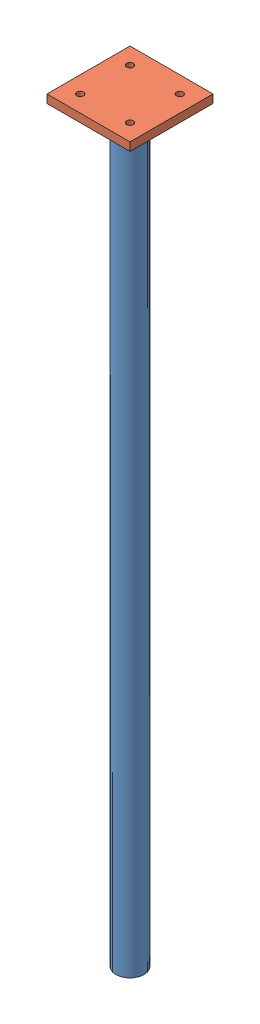
SolidWorks assembly НожкаУГ, configuration По умолчанию. Lengths in mm.
Overall size (100 910 100).
2 component instances, 2 part files, 3 mates.
Components (placement in the parent):
- Ножка-1: Ножка [По умолчанию] at origin size (34 900 34)
- ПланкаУГл-1: ПланкаУГл [По умолчанию] at (0 910 0) x (0 0 -1) z (-1 0 0) size (100 10 100)
Mates (geometry in assembly coordinates):
- Совпадение10: coincident anti-aligned: plane of Ножка-1 through (0 900 0) normal (0 1 0); plane of ПланкаУГл-1 through (0 900 0) normal (0 -1 0)
- Расстояние1: distance = 50 mm anti-aligned: plane of ПланкаУГл-1 through (-50 900 50) normal (-1 0 0); plane of assembly
- Расстояние2: distance = 50 mm anti-aligned: plane of ПланкаУГл-1 through (-50 900 -50) normal (0 0 -1); plane of assembly
